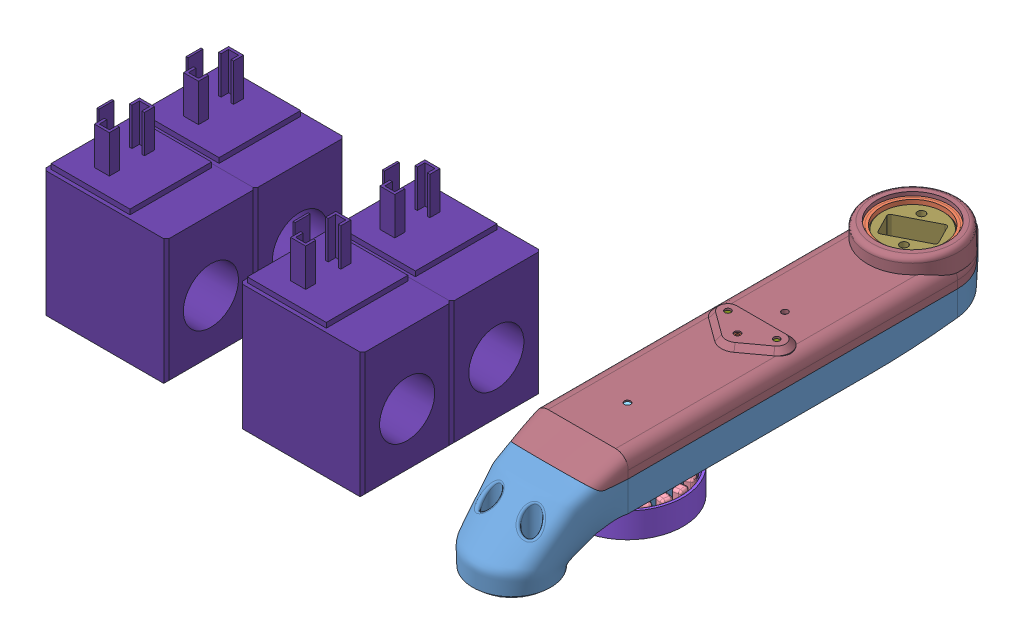
SolidWorks assembly actuator core assembly 2, configuration Default. Lengths in mm.
Overall size (205.67 77.62 198.25).
32 component instances, 17 part files, 38 mates.
Components (placement in the parent):
- upper limb base-1: upper limb base [Default] at (70.7092 92.7911 149.0007) size (48.51 37.5 198.25)
  - upper leg module shell base-1: upper leg module shell base [Default] x (-1 0 0) z (0 0 -1) size (37.01 37.5 198.25)
  - bearing 32x25x4mm-1: bearing 32x25x4mm [Default] at (0 0.5 -61) x (0.90658 0 0.422034) z (-0.422034 0 0.90658) size (32 4 32)
  - bearing 8mm x 3mm x 3mm-1: bearing 8mm x 3mm x 3mm [Default] at (0 -1.5 8.9) x (1 0 0) z (0 -1 0) size (7.96 7.96 3)
- motor rotor-1: motor rotor [Default] at (70.7092 85.0911 201.8007) x (0 0 -1) z (-1 0 0) size (40 13.5 39.72)
- motor assembly-2: motor assembly [Default] at (70.7092 72.4911 201.8007) x (-0.761097 0 -0.648639) z (-0.648639 0 0.761097) size (16.67 33.4 16.67)
  - motor shaft-1: motor shaft [Default] x (1 0 0) z (0 -1 0) size (3.99 3.99 33.4)
  - motor pulley-1: motor pulley [Default] at (0 -20.1 0) x (1 0 0) z (0 -1 0) size (8.98 9.1 6.7)
  - encoder wheel mount-1: encoder wheel mount [Default] at (0 -28.3 0) x (-0.562764 0 0.826618) z (-0.826618 0 -0.562764) size (12 5.96 12)
- motor stator-1: motor stator [Default] at (70.7092 85.0911 201.8007) x (0.629554 0 -0.776957) z (0 -1 0) size (44.35 44.35 16.24)
- B18.6.7M - M3 x 0.5 x 5 Type I Cross Recessed FHMS --5S-1: B18.6.7M - M3 x 0.5 x 5 Type I Cross Recessed FHMS --5S [B18.6.7M - M3 x 0.5 x 5 Type I Cross Recessed FHMS --5S] at (83.2092 94.5911 201.8007) x (0 -1 0) z (-0.166423 0 0.986054) size (5 5.5 5.5)
- B18.6.7M - M3 x 0.5 x 5 Type I Cross Recessed FHMS --5S-2: B18.6.7M - M3 x 0.5 x 5 Type I Cross Recessed FHMS --5S [B18.6.7M - M3 x 0.5 x 5 Type I Cross Recessed FHMS --5S] at (70.7092 94.5911 214.3007) x (0 -1 0) z (0.029806 0 0.999556) size (5 5.5 5.5)
- B18.6.7M - M3 x 0.5 x 5 Type I Cross Recessed FHMS --5S-3: B18.6.7M - M3 x 0.5 x 5 Type I Cross Recessed FHMS --5S [B18.6.7M - M3 x 0.5 x 5 Type I Cross Recessed FHMS --5S] at (58.2092 94.5911 201.8007) x (0 -1 0) z (0.999629 0 -0.027231) size (5 5.5 5.5)
- B18.6.7M - M3 x 0.5 x 5 Type I Cross Recessed FHMS --5S-4: B18.6.7M - M3 x 0.5 x 5 Type I Cross Recessed FHMS --5S [B18.6.7M - M3 x 0.5 x 5 Type I Cross Recessed FHMS --5S] at (70.7092 94.5911 189.3007) x (0 -1 0) z (-0.93368 0 0.358107) size (5 5.5 5.5)
- centre pulley-1: centre pulley [Default] at (66.4357 80.4446 131.9015) x (0.990944 0 0.134278) z (-0.134278 0 0.990944) size (30 19 30)
  - transmission pulley centre-1: transmission pulley centre [Default] at (7.726 11.8465 25.1899) size (30 6.8 30)
  - centre pulley-1: centre pulley [Default] at (7.726 25.3465 25.1899) x (0.694658 0 -0.71934) z (0 -1 0) size (8.98 9.1 19)
- transmission pulley output-1: transmission pulley output [Default] at (70.7092 97.7911 88.0007) x (-0.454924 0 -0.89053) z (0.89053 0 -0.454924) size (29 16.4 29)
- upper leg module cover-1: upper leg module cover [Default] at (70.7092 98.7911 142.6299) x (0 0 1) z (-1 0 0) size (170.23 17.96 37.06)
- bearing 32x25x4mm-1: bearing 32x25x4mm [Default] at (70.7092 107.2911 88.0007) size (32 4 32)
- bearing 8mm x 3mm x 3mm-1: bearing 8mm x 3mm x 3mm [Default] at (70.7092 107.2911 157.9007) x (1 0 0) z (0 -1 0) size (7.96 7.96 3)
- transmission belt tension roller-1: transmission belt tension roller [Default] at (60.9592 99.8911 152.0007) x (0.454066 0 0.890968) z (-0.890968 0 0.454066) size (10 4 10)
- bearing 7mm x 3mm x 3mm-2: bearing 7mm x 3mm x 3mm [Default] at (60.9592 103.8911 152.0007) x (0.030533 0 0.999534) z (0 -1 0) size (7 7 3)
- transmission belt tension roller-2: transmission belt tension roller [Default] at (80.4592 99.8911 152.0007) x (0.177081 0 -0.984196) z (0.984196 0 0.177081) size (10 4 10)
- bearing 7mm x 3mm x 3mm-3: bearing 7mm x 3mm x 3mm [Default] at (80.4592 103.8911 152.0007) x (0 0 -1) z (0 -1 0) size (7 7 3)
- flat head screw_am-1: flat head screw_am [B18.6.7M - M3 x 0.5 x 8 Type I Cross Recessed FHMS --8S] at (60.9592 100.0411 152.0007) x (0 1 0) z (0.851744 0 -0.523958) size (8 5.5 5.5)
- flat head screw_am-2: flat head screw_am [B18.6.7M - M3 x 0.5 x 8 Type I Cross Recessed FHMS --8S] at (80.4592 100.0411 152.0007) x (0 1 0) z (0.851744 0 -0.523958) size (8 5.5 5.5)
- solenoid batteries 2 set-1: solenoid batteries 2 set [Default] at (-44.686 69.2227 130.0865) size (127.33 67 71.12)
  - solenoid coil-1: solenoid coil [Default] at (-59.0806 35.2476 76.9057) x (0 1 0) z (1 0 0) size (67 35.56 49)
  - solenoid coil-2: solenoid coil [Default] at (-59.0806 35.2476 112.4657) x (0 1 0) z (1 0 0) size (67 35.56 49)
  - solenoid coil-3: solenoid coil [Default] at (19.2455 35.2476 76.9057) x (0 1 0) z (1 0 0) size (67 35.56 49)
  - solenoid coil-4: solenoid coil [Default] at (19.2455 35.2476 112.4657) x (0 1 0) z (1 0 0) size (67 35.56 49)
Mates (geometry in assembly coordinates):
- Concentric1: concentric aligned: cylinder of upper limb base-1/upper leg module shell base-1 through (70.7092 93.0911 201.8007) axis (0 -1 0) radius 15.25; cylinder of motor rotor-1 through (70.7092 92.5911 201.8007) axis (0 -1 0) radius 15
- Concentric2: concentric anti-aligned: cylinder of upper limb base-1/upper leg module shell base-1 through (70.7092 64.5911 189.3007) axis (0 1 0) radius 1.6; cylinder of motor rotor-1 through (70.7092 92.5911 189.3007) axis (0 -1 0) radius 2
- Coincident1: coincident anti-aligned: plane of upper limb base-1/upper leg module shell base-1 through (70.7092 92.5911 201.8007) normal (0 -1 0); plane of motor rotor-1 through (70.7092 92.5911 201.8007) normal (0 1 0)
- Concentric3: concentric aligned: line of motor rotor-1 through (70.7092 92.5911 201.8007) axis (0 -1 0); cylinder of motor assembly-2/motor shaft-1 through (70.7092 105.8911 201.8007) axis (0 -1 0) radius 1.995
- Coincident2: coincident anti-aligned: plane of motor rotor-1 through (70.7092 92.5911 201.8007) normal (0 1 0); plane of motor assembly-2/motor pulley-1 through (70.7092 92.5911 201.8007) normal (0 -1 0)
- Concentric4: concentric aligned: cylinder of motor assembly-2/motor shaft-1 through (70.7092 105.8911 201.8007) axis (0 -1 0) radius 1.995; cylinder of motor stator-1 through (70.7092 75.0911 201.8007) axis (0 -1 0) radius 2
- Coincident3: coincident aligned: plane of motor rotor-1 through (70.7092 85.0911 201.8007) normal (0 1 0); plane of motor stator-1 through (70.7092 85.0911 201.8007) normal (0 1 0)
- Concentric5: concentric anti-aligned: cylinder of motor rotor-1 through (70.7092 92.5911 189.3007) axis (0 -1 0) radius 2; cylinder of B18.6.7M - M3 x 0.5 x 5 Type I Cross Recessed FHMS --5S-4 through (70.7092 100.9411 189.3007) axis (0 1 0) radius 1.5
- Concentric6: concentric anti-aligned: cylinder of motor rotor-1 through (58.2092 92.5911 201.8007) axis (0 -1 0) radius 2; cylinder of B18.6.7M - M3 x 0.5 x 5 Type I Cross Recessed FHMS --5S-3 through (58.2092 100.9411 201.8007) axis (0 1 0) radius 1.5
- Concentric7: concentric anti-aligned: cylinder of motor rotor-1 through (70.7092 92.5911 214.3007) axis (0 -1 0) radius 2; cylinder of B18.6.7M - M3 x 0.5 x 5 Type I Cross Recessed FHMS --5S-2 through (70.7092 100.9411 214.3007) axis (0 1 0) radius 1.5
- Concentric8: concentric anti-aligned: cylinder of motor rotor-1 through (83.2092 92.5911 201.8007) axis (0 -1 0) radius 2; cylinder of B18.6.7M - M3 x 0.5 x 5 Type I Cross Recessed FHMS --5S-1 through (83.2092 100.9411 201.8007) axis (0 1 0) radius 1.5
- Coincident4: coincident aligned: plane of upper limb base-1/upper leg module shell base-1 through (70.7092 94.5911 201.8007) normal (0 1 0); plane of B18.6.7M - M3 x 0.5 x 5 Type I Cross Recessed FHMS --5S-4 through (70.7092 94.5911 189.3007) normal (0 1 0)
- Coincident5: coincident aligned: plane of upper limb base-1/upper leg module shell base-1 through (70.7092 94.5911 201.8007) normal (0 1 0); plane of B18.6.7M - M3 x 0.5 x 5 Type I Cross Recessed FHMS --5S-3 through (58.2092 94.5911 201.8007) normal (0 1 0)
- Coincident6: coincident aligned: plane of upper limb base-1/upper leg module shell base-1 through (70.7092 94.5911 201.8007) normal (0 1 0); plane of B18.6.7M - M3 x 0.5 x 5 Type I Cross Recessed FHMS --5S-1 through (83.2092 94.5911 201.8007) normal (0 1 0)
- Coincident7: coincident aligned: plane of upper limb base-1/upper leg module shell base-1 through (70.7092 94.5911 201.8007) normal (0 1 0); plane of B18.6.7M - M3 x 0.5 x 5 Type I Cross Recessed FHMS --5S-2 through (70.7092 94.5911 214.3007) normal (0 1 0)
- Concentric9: concentric anti-aligned: line of upper limb base-1/bearing 8mm x 3mm x 3mm-1 through (70.7092 91.0911 157.9007) axis (0 -1 0); cylinder of centre pulley-1/centre pulley-1 through (70.7092 89.2911 157.9007) axis (0 1 0) radius 1.995
- Coincident9: coincident anti-aligned: plane of upper limb base-1/bearing 8mm x 3mm x 3mm-1 through (70.7092 91.2911 157.9007) normal (0 1 0); plane of centre pulley-1/centre pulley-1 through (70.7092 91.2911 157.9007) normal (0 -1 0)
- Concentric11: concentric anti-aligned: cylinder of upper limb base-1/bearing 32x25x4mm-1 through (70.7092 97.2911 88.0007) axis (0 -1 0) radius 12.5; cylinder of transmission pulley output-1 through (70.7092 93.4411 88.0007) axis (0 1 0) radius 12.575
- Coincident12: coincident anti-aligned: plane of upper limb base-1/bearing 32x25x4mm-1 through (70.7092 97.2911 88.0007) normal (0 1 0); plane of transmission pulley output-1 through (70.7092 97.2911 88.0007) normal (0 -1 0)
- Concentric12: concentric aligned: circle of upper limb base-1/bearing 32x25x4mm-1; cylinder of upper leg module cover-1 through (70.7092 87.7911 88.0007) axis (0 1 0) radius 14.25
- Coincident20: coincident aligned: plane of upper limb base-1/upper leg module shell base-1 through (89.2092 86.7911 109.0007) normal (1 0 0); plane of upper leg module cover-1 through (89.2092 106.7911 219.9999) normal (1 0 0)
- Coincident24: coincident anti-aligned: plane of upper leg module cover-1 through (70.7092 107.2911 157.9007) normal (0 -1 0); plane of bearing 8mm x 3mm x 3mm-1 through (70.7092 107.2911 157.9007) normal (0 1 0)
- Concentric16: concentric anti-aligned: cylinder of upper leg module cover-1 through (70.7092 107.2911 157.9007) axis (0 -1 0) radius 3.98; cylinder of bearing 8mm x 3mm x 3mm-1 through (70.7092 104.2911 157.9007) axis (0 1 0) radius 3.98
- Concentric17: concentric anti-aligned: cylinder of upper leg module cover-1 through (70.7092 100.7911 88.0007) axis (0 1 0) radius 16.4954; cylinder of bearing 32x25x4mm-1 through (70.7092 111.2911 88.0007) axis (0 -1 0) radius 16
- Coincident25: coincident anti-aligned: plane of upper leg module cover-1 through (70.7092 111.2911 88.0007) normal (0 -1 0); plane of bearing 32x25x4mm-1 through (70.7092 111.2911 88.0007) normal (0 1 0)
- Concentric18: concentric anti-aligned: cylinder of transmission belt tension roller-1 through (60.9592 103.8911 152.0007) axis (0 -1 0) radius 3.5; cylinder of bearing 7mm x 3mm x 3mm-2 through (60.9592 100.8911 152.0007) axis (0 1 0) radius 3.5
- Coincident29: coincident anti-aligned: plane of transmission belt tension roller-1 through (60.9592 100.8911 152.0007) normal (0 1 0); plane of bearing 7mm x 3mm x 3mm-2 through (60.9592 100.8911 152.0007) normal (0 -1 0)
- Coincident30: coincident anti-aligned: plane of upper leg module cover-1 through (60.9592 103.8911 152.0007) normal (0 -1 0); plane of transmission belt tension roller-1 through (60.9592 103.8911 152.0007) normal (0 1 0)
- Concentric19: concentric anti-aligned: cylinder of upper leg module cover-1 through (60.9592 103.8911 152.0007) axis (0 1 0) radius 4; cylinder of transmission belt tension roller-1 through (60.9592 103.8911 152.0007) axis (0 -1 0) radius 5
- Concentric20: concentric anti-aligned: cylinder of transmission belt tension roller-2 through (80.4592 103.8911 152.0007) axis (0 -1 0) radius 3.5; cylinder of bearing 7mm x 3mm x 3mm-3 through (80.4592 100.8911 152.0007) axis (0 1 0) radius 3.5
- Coincident31: coincident anti-aligned: plane of transmission belt tension roller-2 through (80.4592 100.8911 152.0007) normal (0 1 0); plane of bearing 7mm x 3mm x 3mm-3 through (80.4592 100.8911 152.0007) normal (0 -1 0)
- Coincident33: coincident anti-aligned: plane of upper leg module cover-1 through (80.4592 103.8911 152.0007) normal (0 -1 0); plane of bearing 7mm x 3mm x 3mm-3 through (80.4592 103.8911 152.0007) normal (0 1 0)
- Concentric22: concentric anti-aligned: cylinder of upper leg module cover-1 through (80.4592 103.8911 152.0007) axis (0 1 0) radius 4; cylinder of transmission belt tension roller-2 through (80.4592 103.8911 152.0007) axis (0 -1 0) radius 5
- Concentric23: concentric anti-aligned: cylinder of bearing 7mm x 3mm x 3mm-2 through (60.9592 100.8911 152.0007) axis (0 1 0) radius 1.5; cylinder of flat head screw_am-1 through (60.9592 93.6911 152.0007) axis (0 -1 0) radius 1.5
- Coincident34: coincident aligned: cone of transmission belt tension roller-1 through (60.9592 100.4911 152.0007) axis (0 1 0); cone of flat head screw_am-1 through (60.9592 100.4911 152.0007) axis (0 1 0)
- Concentric24: concentric anti-aligned: cylinder of bearing 7mm x 3mm x 3mm-3 through (80.4592 100.8911 152.0007) axis (0 1 0) radius 1.5; cylinder of flat head screw_am-2 through (80.4592 93.6911 152.0007) axis (0 -1 0) radius 1.5
- Coincident35: coincident aligned: cone of transmission belt tension roller-2 through (80.4592 100.4911 152.0007) axis (0 1 0); cone of flat head screw_am-2 through (80.4592 100.4911 152.0007) axis (0 1 0)
- Coincident36: coincident anti-aligned: plane of upper limb base-1/upper leg module shell base-1 through (52.2092 98.7911 109.0007) normal (0 1 0); plane of upper leg module cover-1 through (70.7092 98.7911 142.6299) normal (0 -1 0)
